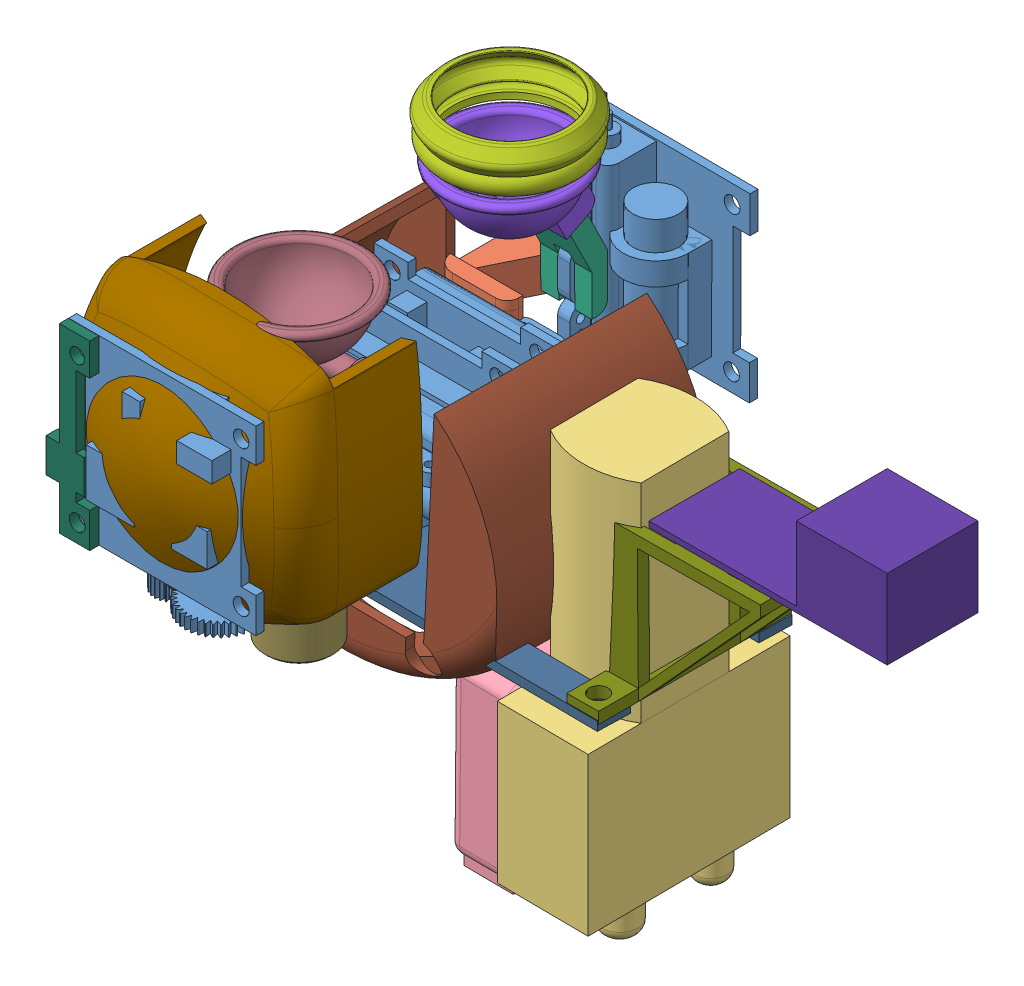
SolidWorks assembly suction_cup_vertical_v8_rotator_assembly, configuration Default. Lengths in mm.
Overall size (42.54 32.56 43.64).
25 component instances, 18 part files, 10 mates.
Components (placement in the parent):
- 1_8grams_linear_servo-1: 1_8grams_linear_servo [Default] at (135.5477 83.6593 7.4339) x (1 0 0) z (0 -1 0) size (21.1 8.5 16.5)
- 1_8grams_linear_servo-2: 1_8grams_linear_servo [Default] at (-146.0418 83.6618 4.5916) x (-1 0 0) z (0 -1 0) size (21.1 8.5 16.5)
- 1_8grams_linear_servo-3: 1_8grams_linear_servo [Default] at (53.6842 167.1936 28.2527) x (0 1 0) z (-1 0 0) size (21.1 8.5 16.5)
- 1_8grams_linear_servo-4: 1_8grams_linear_servo [Default] at (-65.6432 167.4644 -11.9825) x (0.004195 0.999991 0) z (0.999991 -0.004195 0) size (21.1 8.5 16.5)
- servo_suction_cup_arm_right_v6-1: servo_suction_cup_arm_right_v6 [Default] at (-12.0198 22.2382 -0.7799) x (0 0 -1) z (1 0 0) size (12.14 16.03 6.4)
- small_DC_pumP_30kPa-1: small_DC_pumP_30kPa [Default] at (8.0317 -2.9548 6.488) x (-0.999963 0.00865 0.000076) z (0.00865 0.999925 0.008726) size (8 17.8 37.5) (hidden)
- small_DC_pumP_30kPa-2: small_DC_pumP_30kPa [Default] at (-17.6486 -2.7242 6.1215) x (1 0 0) z (0 1 0) size (8 17.8 37.5) (hidden)
- 100mAh_battery_quadcopter-1: 100mAh_battery_quadcopter [Default] at (7.7853 14.7502 0.7807) x (0.008727 0.999962 0) z (0 0 1) size (16 6 15) (hidden)
- silicone_hoses_holder_v2-1: silicone_hoses_holder_v2 [Default] at (7.4051 3.424 8.1829) x (0 0 -1) z (-1 0 0) size (11.4 7.12 8.25)
- suction_cap_arm_v1-1: suction_cap_arm_v1 [Default] at (-8.6298 36.913 -0.2724) x (1 0 0) z (0 0 -1) size (4.5 10.24 4.32)
- suction_cap_arm_v1-2: suction_cap_arm_v1 [Default] at (-4.0823 38.656 16.6687) x (-1 0 0) z (0 0 1) size (4.5 10.24 4.32) (hidden)
- rubber_sleeve_v1-1: rubber_sleeve_v1 [Default] at (-8.7035 37.1255 -0.2562) x (1 0 0) z (0 0 -1) size (12.45 3.78 12.45) (hidden)
- suction_cap_v1-2: suction_cap_v1 [Default] at (-8.6064 37.6021 -0.1642) x (1 0 0) z (0 0.016054 -0.999871) size (12.79 7.19 11.44)
- rubber_sleeve_v1-2: rubber_sleeve_v1 [Default] at (-9.0499 36.943 12.6628) x (1 0 0) z (0 0 -1) size (12.45 3.78 12.45) (hidden)
- Part10^suction_cup_vertical_v8_rotator_assembly-1: Part10^suction_cup_vertical_v8_rotator_assembly [Default] at (53.6842 167.1936 29.2527) x (0 -1 0) z (0 0 1) (virtual)
- casing_arm-2: casing_arm [Default] at (-8.2868 41.4451 17.5869) x (-1 0 0) z (0 0 1) size (22.46 22.88 17.06) (hidden)
- casing_arm-4: casing_arm [Default] at (-4.5129 40.9227 -6.9852) x (0.999962 0.008721 0.000001) z (-0.000001 0.000305 -1) size (22.46 22.88 17.06) (hidden)
- PCB_SkinBot_tethered_v1-1: PCB_SkinBot_tethered_v1 [Default] at (93.7183 13.809 71.3913) x (-0.999962 0 -0.008727) z (-0.000152 -0.999848 0.017452) size (42.4 17.02 5.02)
- casing_body_v1-1: casing_body_v1 [Default] at (-6.4853 6.1324 14.8952) x (0.999353 -0.034899 0.008721) z (0.008727 0 -0.999962) size (29.65 23.8 19.79) (hidden)
- TGPP06-D-136-1: TGPP06-D-136 [Default] at (-6.2766 10.1401 18.1954) x (1 0 0) z (0 1 0) size (6 6 21.6)
- suction_cap_v1_for_motor_0_5_offset-1: suction_cap_v1_for_motor_0_5_offset [Default] at (-3.7789 36.9401 18.1954) x (-1 0 0) z (0 0 1) size (12.79 8.11 11.44)
- motor_connector_v1-1: motor_connector_v1 [Default] at (-5.7466 23.6807 23.2003) x (-0.999962 0 -0.008727) z (0 -1 0) size (7.99 8.03 6)
- servo_suction_cup_arm_left_v6_motor-1: servo_suction_cup_arm_left_v6_motor [Default] at (-10.2518 25.2809 18.1181) x (0 0 1) z (1 0 0) size (16.54 16 10.33)
- camera_mount_v1-1: camera_mount_v1 [Default] at (15.3621 14.3249 33.817) x (0 0 1) z (0.999962 0.008727 0) size (16.98 26.65 24.5) (hidden)
- spy_cam_V1-1: spy_cam_V1 [Default] at (19.852 26.1537 8.2556) x (-1 0 0) z (0 0 -1) size (21 7 8) (hidden)
Mates (geometry in assembly coordinates):
- Parallel8: parallel anti-aligned: plane of 1_8grams_linear_servo-1 through (135.5477 83.6593 8.1339) normal (0 0 1); plane of 1_8grams_linear_servo-3 through (53.6842 167.1936 27.5527) normal (0 0 -1)
- Parallel9: parallel: plane of 1_8grams_linear_servo-2 through (-146.0418 83.6618 3.8916) normal (0 0 -1); plane of 1_8grams_linear_servo-4 through (-65.6432 167.4644 -11.2825) normal (0 0 1)
- Coincident37: coincident anti-aligned: plane of 1_8grams_linear_servo-3 through (53.6842 167.1936 23.2527) normal (0 0 -1); plane of suction_cap_arm_v1-2 through (-8.5823 29.9772 23.2527) normal (0 0 1)
- Coincident38: coincident anti-aligned: plane of 1_8grams_linear_servo-3 through (-5.6941 28.5458 21.4527) normal (1 0 0); plane of suction_cap_arm_v1-2 through (-5.6941 29.9678 17.3528) normal (-1 0 0)
- InPlace1: in place: plane of ? through (53.6842 167.1936 25.3734) normal (0 0 1); plane of ? through (0 0 25.3734) normal (0 0 1); moOrthogonalPlaneRef_w of ? through (53.6842 167.1936 25.3734) normal (0 0 1); plane of ? through (0 0 25.3734) normal (0 1 0); plane of ? through (53.6842 167.1936 25.3734) normal (0 0 1); plane of ? through (0 0 25.3734) normal (1 0 0); plane of 1_8grams_linear_servo-3 through (53.6842 167.1936 29.2527) normal (0 0 1); unknown of Part10^suction_cup_vertical_v8_rotator_assembly-1
- Coincident52: coincident aligned: plane of 1_8grams_linear_servo-3; plane of Part10^suction_cup_vertical_v8_rotator_assembly-1
- Coincident53: coincident aligned: moOrthogonalPlaneRef_w of 1_8grams_linear_servo-3 through (53.6842 167.1936 29.2527) normal (1 0 0); plane of Part10^suction_cup_vertical_v8_rotator_assembly-1 through (53.6842 167.1936 29.2527) normal (1 0 0)
- Coincident54: coincident anti-aligned: moOrthogonalPlaneRef_w of 1_8grams_linear_servo-3 through (53.6842 167.1936 29.2527) normal (0 1 0); plane of Part10^suction_cup_vertical_v8_rotator_assembly-1 through (53.6842 167.1936 29.2527) normal (0 -1 0)
- Coincident54: coincident anti-aligned: plane of TGPP06-D-136-1 through (-6.2766 29.2401 18.1954) normal (0 1 0); plane of suction_cap_v1_for_motor_0_5_offset-1 through (-6.2766 29.2401 18.1954) normal (0 -1 0)
- Coincident56: coincident anti-aligned: plane of 1_8grams_linear_servo-1 through (-12.5518 24.2809 18.9391) normal (-1 0 0); plane of servo_suction_cup_arm_left_v6_motor-1 through (-12.5518 23.2059 14.5381) normal (1 0 0)
